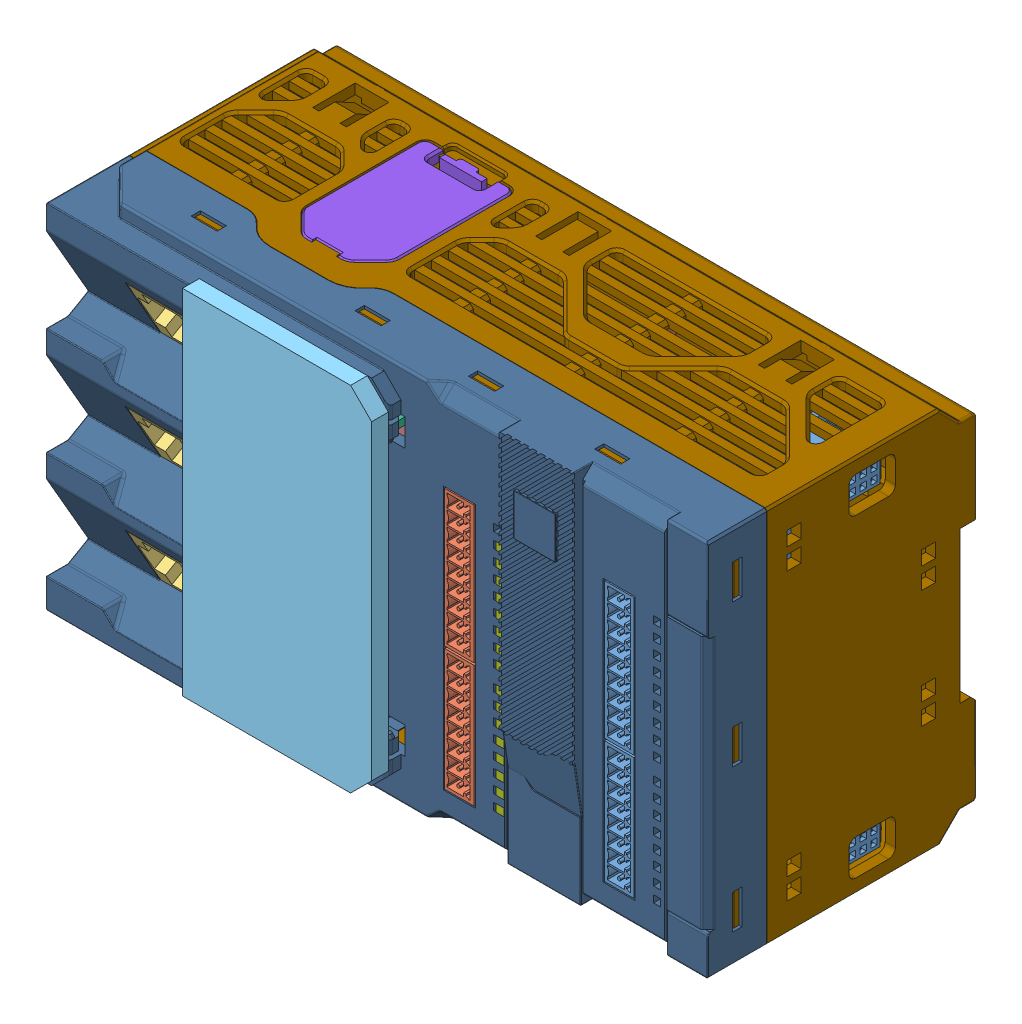
SolidWorks assembly PLC(凌臣)-总装图_221215(4).STEP, configuration 默认. Lengths in mm.
Overall size (152.02 90.07 71).
12 component instances, 12 part files, 0 mates.
Components (placement in the parent):
- PLC(____)-PCB-1_D__.STEP-1: PLC(____)-PCB-1_D__.STEP [默认] at (60.05 0 -25.75) x (0 -1 0) z (-1 0 0) size (84 47.5 22.5)
- PLC(____)-PCB-2_D__.STEP-1: PLC(____)-PCB-2_D__.STEP [默认] at (22.05 0 -25.75) x (0 -1 0) z (-1 0 0) size (84 47.5 9.55)
- PLC(____)-PCB-3_D__.STEP-1: PLC(____)-PCB-3_D__.STEP [默认] at (-1 0 -52.45) x (0 1 0) z (0 0 1) size (118.86 195.16 52.21) (hidden)
- PLC(____)-PCB-4_D__.STEP-1: PLC(____)-PCB-4_D__.STEP [默认] at (-43.75 0 -22.5) x (0 -1 0) z (-1 0 0) size (84 51.32 19.13)
- PLC(____)-PCB-5_D__.STEP-1: PLC(____)-PCB-5_D__.STEP [默认] at (-16.1 0 -26) x (0 1 0) z (-1 0 0) size (86.3 48.81 14.15)
- PLC(____)-LOGO_____C__.STEP-1: PLC(____)-LOGO_____C__.STEP [默认] at (-19.5 0 3) size (45 84 4)
- ______A_C__.STEP-1: ______A_C__.STEP [默认] at (-3.85 30.45 -5) x (0 0 1) z (-1 0 0) size (16 18.2 10.9)
- ______B_C__.STEP-1: ______B_C__.STEP [默认] at (26.3 -7.75 -14) size (5.15 65.8 16)
- ______1.STEP-1: ______1.STEP [默认] at (82.187 0.05 -58.9589) x (-1 0 0) z (0 1 0) size (21.7 35.5 26.54)
- PRT0021_82_1.STEP-1: PRT0021_82_1.STEP [默认] at (82.25 0 -60) x (-1 0 0) z (0 1 0) size (152 57.9 90)
- LC-PLC-____.STEP-1: LC-PLC-____.STEP [默认] at (82.25 0 -60) x (-1 0 0) z (0 1 0) size (152.02 23.93 90.04)
- PLC(____)-_____________.STEP-1: PLC(____)-_____________.STEP [默认] at (-82.25 0 -59.9) x (1 0 0) z (0 -1 0) size (33.8 4 30.9)
